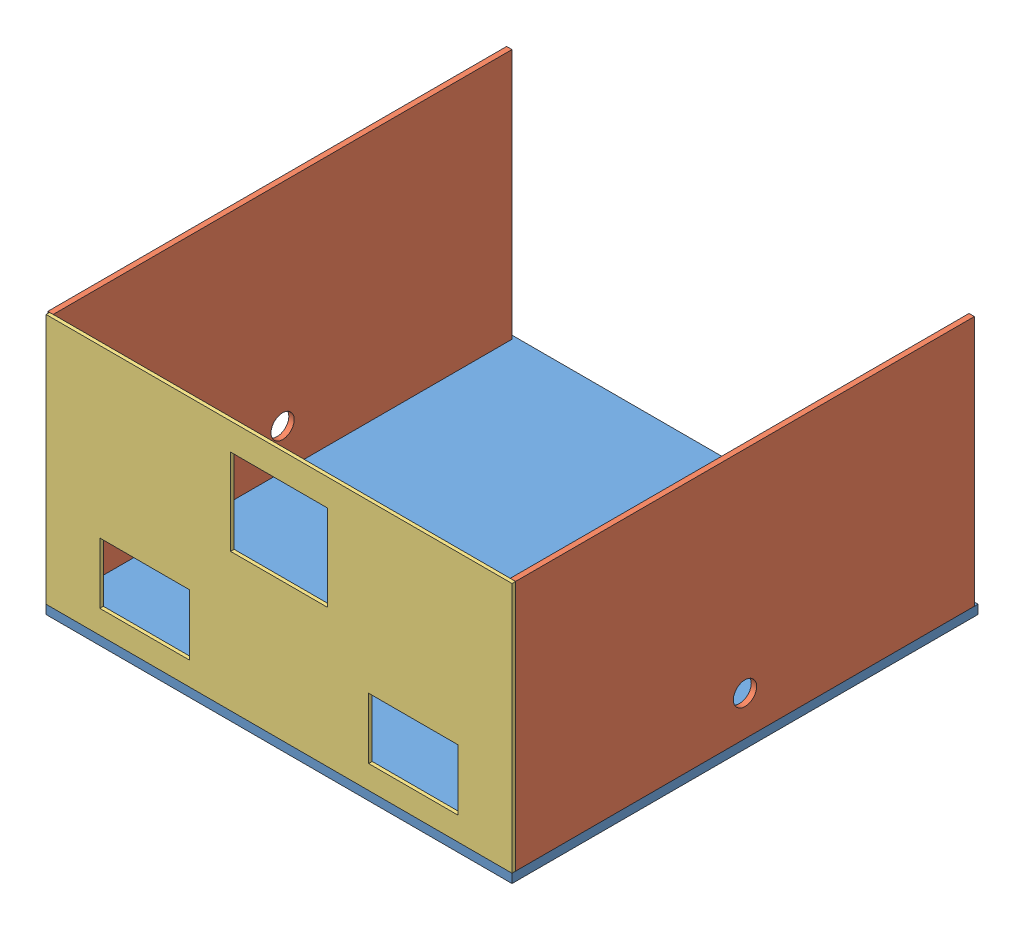
SolidWorks assembly Assembled_Case, configuration Default. Lengths in mm.
Overall size (130 72.5 130).
4 component instances, 3 part files, 6 mates.
Components (placement in the parent):
- Bottom-1: Bottom [Default] at (59.0725 57.0515 100.7017) size (130 2.5 130)
- Side-side-1: Side-side [Default] at (-4.9275 94.5515 100.7017) x (0 0 1) z (-1 0 0) size (128 70 1.5)
- Side-side-2: Side-side [Default] at (124.0725 94.5515 100.7017) x (0 0 1) z (-1 0 0) size (128 70 1.5)
- Front-side-1: Front-side [Default] at (59.0725 94.5515 164.7017) size (130 70 1)
Mates (geometry in assembly coordinates):
- Coincident1: coincident anti-aligned: plane of Bottom-1 through (59.0725 59.5515 100.7017) normal (0 1 0); plane of Side-side-2 through (123.0725 59.5515 36.7017) normal (0 -1 0)
- Coincident4: coincident aligned: plane of Bottom-1 through (124.0725 59.5515 165.7017) normal (1 0 0); plane of Side-side-2 through (124.0725 94.5515 100.7017) normal (1 0 0)
- Coincident12: coincident anti-aligned: plane of Bottom-1 through (59.0725 59.5515 100.7017) normal (0 1 0); plane of Side-side-1 through (-5.9275 59.5515 36.7017) normal (0 -1 0)
- Coincident16: coincident aligned: plane of Bottom-1 through (-5.9275 59.5515 165.7017) normal (-1 0 0); plane of Side-side-1 through (-5.9275 94.5515 100.7017) normal (-1 0 0)
- Coincident23: coincident anti-aligned: plane of Bottom-1 through (59.0725 59.5515 100.7017) normal (0 1 0); plane of Front-side-1 through (-5.9275 59.5515 165.7017) normal (0 -1 0)
- Coincident25: coincident aligned: plane of Side-side-2 through (124.0725 94.5515 100.7017) normal (1 0 0); plane of Front-side-1 through (124.0725 59.5515 165.7017) normal (1 0 0)
